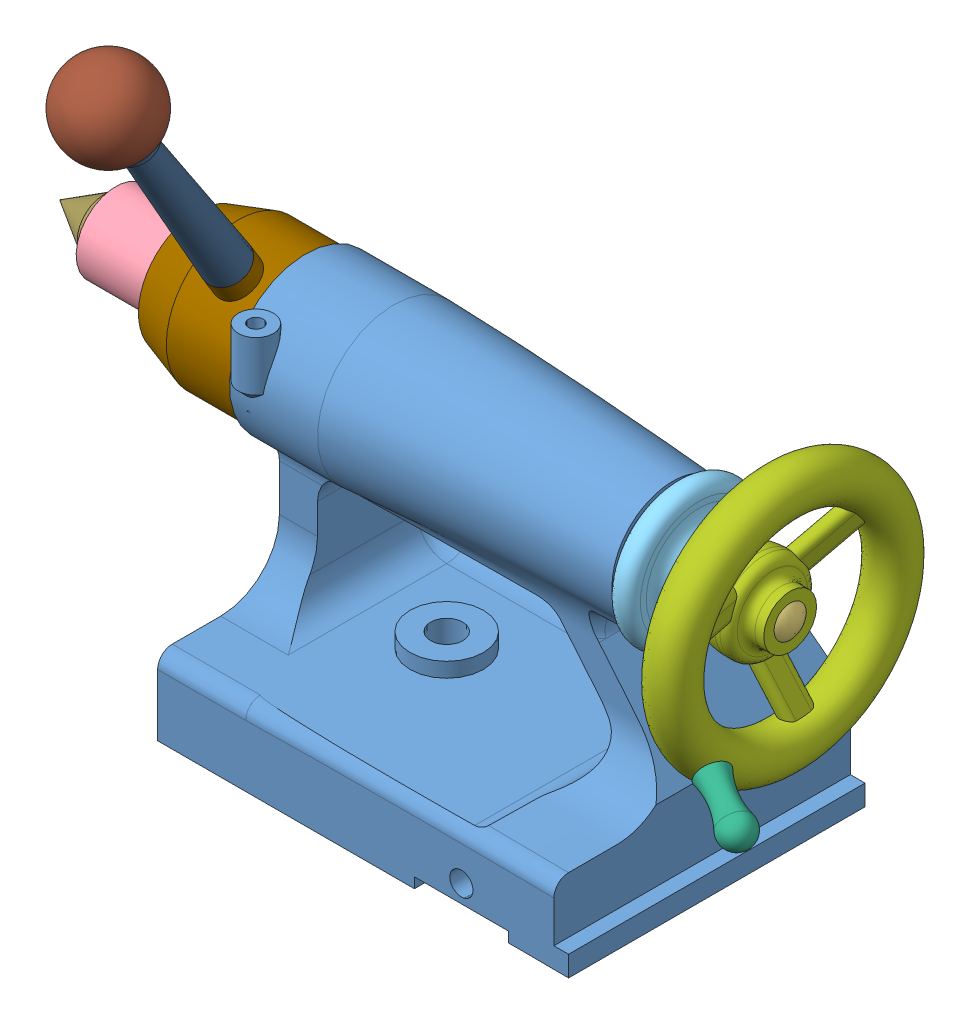
SolidWorks assembly Assem1, configuration Default. Lengths in mm.
Overall size (275.57 205.4 132.66).
12 component instances, 12 part files, 24 mates.
Components (placement in the parent):
- 1.Body-1: 1.Body [Default] at (30.3604 115.1949 97.5267) x (-1 0 0) z (0 1 0) size (172.51 101.29 118.66)
- 9.Shaft Key-1: 9.Shaft Key [Default] at (4.3604 93.9284 95.0267) size (12 10.5 5)
- 3.Screw-1: 3.Screw [Default] at (18.3604 115.1949 97.5267) x (1 0 0) z (0 0.958081 -0.286498) size (150.19 19 19)
- 4.Morse Tapper Tool-1: 4.Morse Tapper Tool [Default] at (-64.3793 115.1949 97.5267) x (1 0 0) z (0 0 -1) size (156.97 26.77 27)
- 10.tailstock bush-1: 10.tailstock bush [Default] at (114.3604 115.1949 97.5267) x (1 0 0) z (0 -0.279894 0.960031) size (27 48 48)
- 5.Crank Wheel-1: 5.Crank Wheel [Default] at (183.9529 81.4209 134.347) x (-0.860918 0.343892 -0.37491) z (-0.493898 -0.388244 0.77803) size (29.5 11 11)
- 2.Wheel-1: 2.Wheel [Default] at (141.3604 115.1949 97.5267) x (1 0 0) z (0 -0.958081 0.286498) size (29.01 90 90)
- 12.Pin-2: 12.Pin [Default] at (145.3604 115.1949 97.5267) x (1 0 0) z (0 -0.286498 -0.958081) size (4 4 28)
- 11.Tailstock Ram-1: 11.Tailstock Ram [Default] at (-36.6396 115.1949 97.5267) x (1 0 0) z (0 -0.523571 0.851982) size (38 55 49)
- 7.handle-1: 7.handle [Default] at (-10.6396 136.0684 110.3542) x (0 0.851982 0.523571) z (-0.809189 0.307623 -0.500581) size (78 14 14)
- 6.knob-1: 6.knob [Default] at (-10.6396 206.783 153.8105) x (-0.759482 0.603903 0.241841) z (-0.582843 -0.796808 0.159346) size (30 30 30)
- 8.Tailstock Center-1: 8.Tailstock Center [Default] at (-83.4936 115.1949 97.5267) x (1 0 0) z (0 0.601639 0.798768) size (90 18 18)
Mates (geometry in assembly coordinates):
- Width1: width anti-aligned: plane of 9.Shaft Key-1 through (4.3604 93.9284 100.0267) normal (-1 0 0); plane of 1.Body-1 through (9.3604 101.9284 100.0267) normal (1 0 0); plane of 9.Shaft Key-1 through (4.3604 -7.3117 100.0267) normal (1 0 0); plane of 1.Body-1 through (9.3604 -7.3117 100.0267) normal (-1 0 0)
- Coincident1: coincident anti-aligned: plane of 1.Body-1 through (9.3604 -7.3117 95.0267) normal (0 0 1); plane of 9.Shaft Key-1 through (4.3604 93.9284 95.0267) normal (0 0 -1)
- Coincident2: coincident: cylinder of 1.Body-1 through (0.3604 115.1949 97.5267) axis (1 0 0) radius 13.5; line of 9.Shaft Key-1 through (0.8604 101.9284 95.0267) axis (1 0 0)
- Concentric1: concentric aligned: cylinder of 1.Body-1 through (0.3604 115.1949 97.5267) axis (1 0 0) radius 13.5; cone of 4.Morse Tapper Tool-1 through (-64.3793 115.1949 97.5267) axis (1 0 0)
- Parallel1: parallel anti-aligned: plane of 9.Shaft Key-1 through (4.3604 93.9284 95.0267) normal (0 0 -1); plane of 4.Morse Tapper Tool-1 through (92.5877 101.6949 95.0267) normal (0 0 1)
- Concentric2: concentric anti-aligned: cylinder of 1.Body-1 through (0.3604 115.1949 97.5267) axis (1 0 0) radius 13.5; cylinder of 3.Screw-1 through (18.3604 115.1949 97.5267) axis (-1 0 0) radius 5.5
- Screw1: screw = 1 mm aligned: cylinder of 3.Screw-1 through (18.3604 115.1949 97.5267) axis (-1 0 0) radius 6.5; cylinder of 4.Morse Tapper Tool-1 through (-64.3793 115.1949 97.5267) axis (-1 0 0) radius 7.25
- Concentric3: concentric aligned: cylinder of 3.Screw-1 through (18.3604 115.1949 97.5267) axis (-1 0 0) radius 5.5; cylinder of 10.tailstock bush-1 through (114.3604 115.1949 97.5267) axis (-1 0 0) radius 5.5
- Coincident4: coincident anti-aligned: plane of 3.Screw-1 through (114.3604 113.7624 92.7363) normal (1 0 0); plane of 10.tailstock bush-1 through (114.3604 120.475 99.0661) normal (-1 0 0)
- Coincident5: coincident anti-aligned: plane of 1.Body-1 through (125.3604 115.1949 97.5267) normal (1 0 0); plane of 10.tailstock bush-1 through (125.3604 127.8385 101.2129) normal (-1 0 0)
- Concentric4: concentric aligned: cylinder of 3.Screw-1 through (18.3604 115.1949 97.5267) axis (-1 0 0) radius 5.5; cylinder of 2.Wheel-1 through (141.3604 115.1949 97.5267) axis (-1 0 0) radius 5.5
- Concentric8: concentric aligned: cylinder of 3.Screw-1 through (18.3604 115.1949 97.5267) axis (-1 0 0) radius 5.5; cylinder of 2.Wheel-1 through (141.3604 115.1949 97.5267) axis (-1 0 0) radius 5.5
- Concentric9: concentric anti-aligned: cylinder of 3.Screw-1 through (145.3604 117.9166 106.6285) axis (0 -0.286498 -0.958081) radius 2; cylinder of 2.Wheel-1 through (145.3604 109.4649 78.3651) axis (0 0.286498 0.958081) radius 2
- Concentric10: concentric aligned: cylinder of 2.Wheel-1 through (145.3604 109.4649 78.3651) axis (0 0.286498 0.958081) radius 2; cylinder of 12.Pin-2 through (145.3604 111.1839 84.1136) axis (0 0.286498 0.958081) radius 2
- Coincident9: coincident anti-aligned: plane of 2.Wheel-1 through (141.3604 115.1949 97.5267) normal (0 0.286498 0.958081); plane of 12.Pin-2 through (145.3604 115.1949 97.5267) normal (0 -0.286498 -0.958081)
- Concentric11: concentric aligned: cylinder of 5.Crank Wheel-1 through (183.9529 81.4209 134.347) axis (0.860918 -0.343892 0.37491) radius 3; cylinder of 2.Wheel-1 through (169.3173 87.267 127.9736) axis (0.860918 -0.343892 0.37491) radius 2.5
- Tangent2: tangent anti-aligned: plane of 5.Crank Wheel-1 through (168.9513 84.7021 126.4613) normal (-0.860918 0.343892 -0.37491); torus of 2.Wheel-1
- Concentric12: concentric anti-aligned: cone of 4.Morse Tapper Tool-1 through (-64.3793 115.1949 97.5267) axis (1 0 0); cone of 11.Tailstock Ram-1 through (-33.6396 115.1949 97.5267) axis (-1 0 0)
- Coincident10: coincident anti-aligned: plane of 1.Body-1 through (0.3604 84.6171 116.5267) normal (-1 0 0); plane of 11.Tailstock Ram-1 through (0.3604 136.0684 110.3542) normal (1 0 0)
- Concentric13: concentric anti-aligned: cylinder of 11.Tailstock Ram-1 through (-10.6396 141.1803 113.4956) axis (0 0.851982 0.523571) radius 4.25; cylinder of 7.handle-1 through (-10.6396 136.0684 110.3542) axis (0 -0.851982 -0.523571) radius 5
- Coincident11: coincident anti-aligned: plane of 11.Tailstock Ram-1 through (-10.6396 141.1803 113.4956) normal (0 0.851982 0.523571); plane of 7.handle-1 through (-6.5268 144.146 108.6697) normal (0 -0.851982 -0.523571)
- Concentric14: concentric aligned: cylinder of 7.handle-1 through (-10.6396 136.0684 110.3542) axis (0 -0.851982 -0.523571) radius 4.5; cylinder of 6.knob-1 through (-10.6396 194.0032 145.957) axis (0 -0.851982 -0.523571) radius 5.1
- Tangent3: tangent anti-aligned: plane of 7.handle-1 through (-7.9956 195.9097 142.8546) normal (0 0.851982 0.523571); sphere of 6.knob-1
- Coincident12: coincident anti-aligned: circle of 4.Morse Tapper Tool-1; cone of 8.Tailstock Center-1 through (3.5064 115.1949 97.5267) axis (1 0 0)
